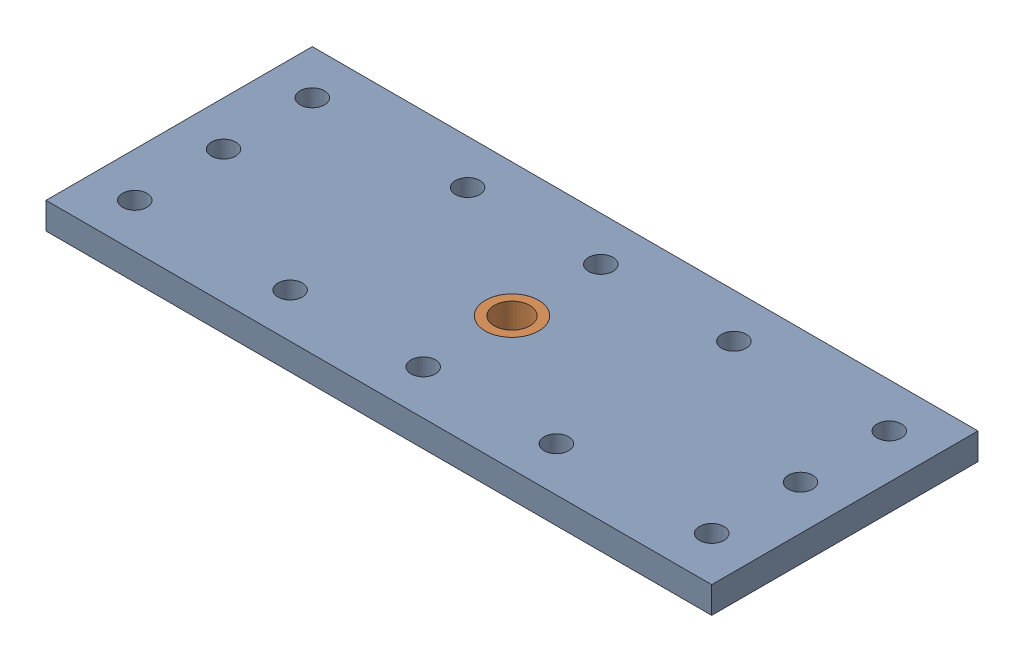
SolidWorks assembly Rear Plate Assembly, configuration Default. Lengths in mm.
Overall size (150 6 60).
2 component instances, 2 part files, 0 mates.
Components (placement in the parent):
- Rear Plate-1: Rear Plate [Default] at origin size (150 6 60)
- 6658K734-1: 6658K734 [Default] at (0 98 30) x (1 0 0) z (0 -1 0) size (12.03 12.03 6)
